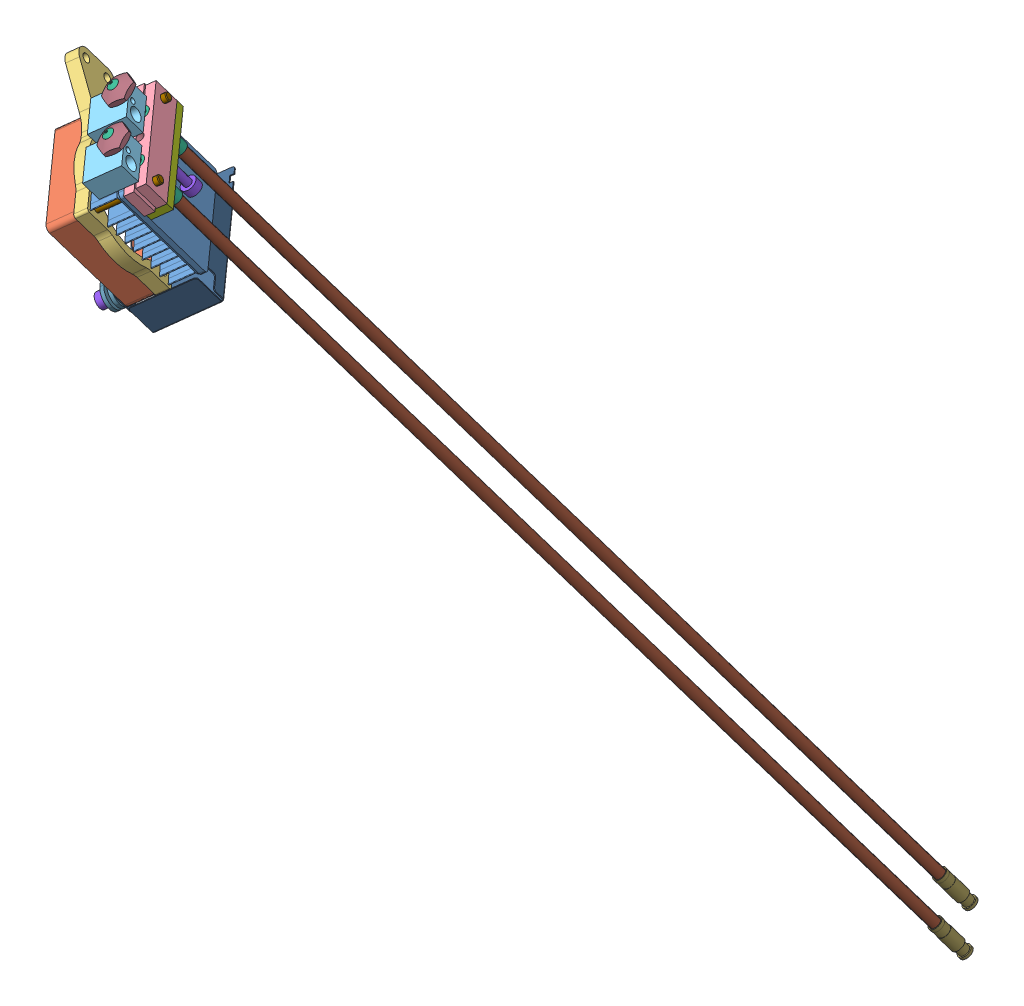
SolidWorks assembly 838, configuration Default. Lengths in mm.
Overall size (182.74 333.87 245.17).
23 component instances, 15 part files, 53 mates.
Components (placement in the parent):
- 357-1: 357 [Default] at (71.5589 -24.0668 51.2021) x (-0.63863 0.214399 -0.739043) z (-0.330371 0.790997 0.514955) size (40 13 40)
- 846-1: 846 [Default] at (59.0492 -34.3813 59.0199) x (-0.63863 0.214399 -0.739043) z (-0.694987 -0.573024 0.434323) size (40 40 10)
- 741-1: 741 [Default] at (59.0492 -34.3813 59.0199) x (0.63863 -0.214399 0.739043) z (0.694987 0.573024 -0.434323) size (59.3 52.5 5)
- 736-1: 736 [Default] at (67.7315 -5.9548 59.7639) x (0.63863 -0.214399 0.739043) z (0.330371 -0.790997 -0.514955) size (42 8 10)
- 739-1: 739 [Default] at (72.4173 -14.8335 80.8745) x (0.694987 0.573024 -0.434323) z (-0.330371 0.790997 0.514955) size (14 14 8)
- 739-2: 739 [Default] at (60.2862 -10.7609 66.8361) x (0.694987 0.573024 -0.434323) z (-0.330371 0.790997 0.514955) size (14 14 8)
- 738-2: 738 [Default] at (79.9671 -22.764 57.1656) x (0.082226 -0.519395 0.850569) z (-0.330371 0.790997 0.514955) size (5 5 33.2)
- 738-3: 738 [Default] at (67.8361 -18.6914 43.1272) x (0.499266 -0.316556 0.806552) z (-0.330371 0.790997 0.514955) size (5 5 33.2)
- 743-1: 743 [Default] at (70.3402 -14.4378 55.0487) x (-0.63863 0.214399 -0.739043) z (0.330371 -0.790997 -0.514955) size (40 8 3)
- 242-1: 242 [Default] at (75.3286 -24.1473 47.9182) x (-0.941272 -0.316416 -0.117844) z (0.330371 -0.790997 -0.514955) size (5.7 5.7 19)
- 520-1: 520 [Default] at (59.1164 -29.1669 82.1241) x (-0.685251 0.344906 -0.64146) z (-0.694987 -0.573024 0.434323) size (5.7 5.7 38)
- 520-2: 520 [Default] at (38.6803 -22.3061 58.4748) x (0.397421 0.197255 0.896185) z (-0.694987 -0.573024 0.434323) size (5.7 5.7 38)
- 891-1: 891 [Default] at (34.0047 -22.8308 58.1292) x (0.330371 -0.790997 -0.514955) z (-0.694987 -0.573024 0.434323) size (19.51 52.71 25.91)
- 242-2: 242 [Default] at (64.3021 -58.9197 69.0116) x (0.494952 -0.819418 -0.289096) z (-0.694987 -0.573024 0.434323) size (5.7 5.7 19)
- 242-3: 242 [Default] at (46.8892 -49.5663 43.4729) x (0.494952 -0.819418 -0.289096) z (-0.694987 -0.573024 0.434323) size (5.7 5.7 19)
- 219-1: 219 [Default] at (190.6262 -312.6844 -148.2683) x (0.896188 0.091701 0.434094) z (-0.330371 0.790997 0.514955) size (4 4 380)
- 219-2: 219 [Default] at (202.7573 -316.757 -134.2298) x (0.896188 0.091701 0.434094) z (-0.330371 0.790997 0.514955) size (4 4 380)
- 106-1: 106 [Default] at (199.6549 -309.3291 -129.3941) x (0.541182 0.605747 -0.58326) z (0.330371 -0.790997 -0.514955) size (5 5 15)
- 106-2: 106 [Default] at (187.5238 -305.2565 -143.4325) x (0.541182 0.605747 -0.58326) z (0.330371 -0.790997 -0.514955) size (5 5 15)
- 794-1: 794 [Default] at (70.3942 0.1562 72.0872) x (0.896188 0.091701 0.434094) z (-0.330371 0.790997 0.514955) size (11.55 10 4.01)
- 794-2: 794 [Default] at (58.2631 4.2288 58.0487) x (0.896188 0.091701 0.434094) z (-0.330371 0.790997 0.514955) size (11.55 10 4.01)
- 841-1: 841 [Default] at (56.454 -52.6174 63.6171) x (0.63863 -0.214399 0.739043) z (0.330371 -0.790997 -0.514955) size (19 7.7 9.6)
- 212-1: 212 [Default] at (64.3021 -58.9197 69.0116) x (-0.547984 0.031038 -0.835912) z (0.694987 0.573024 -0.434323) size (7 7 0.5)
Mates (geometry in assembly coordinates):
- Coincident327: coincident anti-aligned: circle of 738-2; plane of 738-3 through (56.8348 7.8683 60.6713) normal (-0.330371 0.790997 0.514955)
- Concentric245: concentric anti-aligned: cylinder of 739-1 through (70.3942 0.1562 72.0872) axis (-0.330371 0.790997 0.514955) radius 1.65; cylinder of 738-2 through (79.9671 -22.764 57.1656) axis (0.330371 -0.790997 -0.514955) radius 2.5
- Concentric246: concentric anti-aligned: cylinder of 739-2 through (58.2631 4.2288 58.0487) axis (-0.330371 0.790997 0.514955) radius 1.65; cylinder of 738-3 through (67.8361 -18.6914 43.1272) axis (0.330371 -0.790997 -0.514955) radius 2
- Coincident331: coincident anti-aligned: plane of 739-1 through (63.4764 -11.8319 70.5279) normal (0.330371 -0.790997 -0.514955); plane of 738-2 through (73.2263 -7.3664 69.9238) normal (-0.330371 0.790997 0.514955)
- Coincident333: coincident anti-aligned: plane of 846-1 through (59.0492 -34.3813 59.0199) normal (0.694987 0.573024 -0.434323); plane of 741-1 through (59.0492 -34.3813 59.0199) normal (-0.694987 -0.573024 0.434323)
- Coincident335: coincident aligned: plane of 739-1 through (63.4764 -11.8319 70.5279) normal (0.330371 -0.790997 -0.514955); plane of 739-2 through (51.3453 -7.7593 56.4895) normal (0.330371 -0.790997 -0.514955)
- Concentric259: concentric anti-aligned: cylinder of 743-1 through (72.0249 -16.2373 53.0678) axis (-0.330371 0.790997 0.514955) radius 2.2; cylinder of 242-1 through (70.0426 -11.4913 56.1575) axis (0.330371 -0.790997 -0.514955) radius 1.5
- Distance2: distance = 10 mm anti-aligned: plane of 242-1 through (75.3286 -24.1473 47.9182) normal (-0.330371 0.790997 0.514955); plane of 743-1 through (71.3313 -16.8108 53.5038) normal (0.330371 -0.790997 -0.514955)
- Coincident345: coincident anti-aligned: plane of 846-1 through (59.0492 -34.3813 59.0199) normal (0.694987 0.573024 -0.434323); plane of 741-1 through (59.0492 -34.3813 59.0199) normal (-0.694987 -0.573024 0.434323)
- Concentric263: concentric aligned: cylinder of 846-1 through (38.6803 -22.3061 58.4748) axis (-0.694987 -0.573024 0.434323) radius 3.1; cylinder of 741-1 through (47.0201 -15.4298 53.2629) axis (-0.694987 -0.573024 0.434323) radius 1.6
- Concentric264: concentric aligned: cylinder of 846-1 through (59.1164 -29.1669 82.1241) axis (-0.694987 -0.573024 0.434323) radius 3.1; cylinder of 741-1 through (67.4563 -22.2906 76.9122) axis (-0.694987 -0.573024 0.434323) radius 1.6
- Concentric265: concentric anti-aligned: cylinder of 357-1 through (69.5412 -20.5715 75.6093) axis (0.694987 0.573024 -0.434323) radius 1.6; cylinder of 846-1 through (59.1164 -29.1669 82.1241) axis (-0.694987 -0.573024 0.434323) radius 3.1
- Coincident355: coincident anti-aligned: plane of 357-1 through (62.5241 -31.5162 56.8483) normal (-0.694987 -0.573024 0.434323); plane of 741-1 through (62.5241 -31.5162 56.8483) normal (0.694987 0.573024 -0.434323)
- Concentric273: concentric anti-aligned: cylinder of 357-1 through (49.1051 -13.7107 51.9599) axis (0.694987 0.573024 -0.434323) radius 1.6; cylinder of 846-1 through (38.6803 -22.3061 58.4748) axis (-0.694987 -0.573024 0.434323) radius 3.1
- Concentric276: concentric aligned: cylinder of 846-1 through (63.9813 -25.1557 79.0839) axis (-0.694987 -0.573024 0.434323) radius 1.6; cylinder of 520-1 through (83.441 -9.111 66.9228) axis (-0.694987 -0.573024 0.434323) radius 1.5
- Coincident357: coincident anti-aligned: circle of 846-1; plane of 520-1 through (59.1164 -29.1669 82.1241) normal (0.694987 0.573024 -0.434323)
- Concentric277: concentric aligned: cylinder of 846-1 through (38.6803 -22.3061 58.4748) axis (-0.694987 -0.573024 0.434323) radius 3.1; cylinder of 520-2 through (63.0048 -2.2503 43.2734) axis (-0.694987 -0.573024 0.434323) radius 1.5
- Coincident358: coincident anti-aligned: circle of 846-1; plane of 520-2 through (38.6803 -22.3061 58.4748) normal (0.694987 0.573024 -0.434323)
- Concentric280: concentric aligned: cylinder of 846-1 through (69.6883 -54.4788 65.6456) axis (-0.694987 -0.573024 0.434323) radius 3.1; circle of 891-1
- Coincident360: coincident anti-aligned: plane of 846-1 through (52.0993 -40.1115 63.3631) normal (-0.694987 -0.573024 0.434323); plane of 891-1 through (34.2827 -22.6016 57.9555) normal (0.694987 0.573024 -0.434323)
- Concentric284: concentric aligned: cylinder of 738-3 through (67.8361 -18.6914 43.1272) axis (0.330371 -0.790997 -0.514955) radius 2.5; circle of 743-1
- Coincident361: coincident anti-aligned: plane of 357-1 through (89.4855 -42.6667 55.3477) normal (0.694987 0.573024 -0.434323); plane of 736-1 through (55.4841 -11.8694 41.5724) normal (-0.694987 -0.573024 0.434323)
- Concentric285: concentric anti-aligned: cylinder of 736-1 through (77.1007 -15.9011 61.6336) axis (-0.330371 0.790997 0.514955) radius 2.5; cylinder of 738-2 through (79.9671 -22.764 57.1656) axis (0.330371 -0.790997 -0.514955) radius 2.5
- Concentric286: concentric anti-aligned: circle of 736-1; cylinder of 738-3 through (67.8361 -18.6914 43.1272) axis (0.330371 -0.790997 -0.514955) radius 2.5
- Concentric287: concentric aligned: circle of 736-1; circle of 520-1
- Concentric288: concentric aligned: circle of 736-1; circle of 520-2
- Concentric289: concentric aligned: circle of 846-1; circle of 891-1
- Coincident362: coincident aligned: plane of 736-1 through (61.6659 -3.9185 52.7446) normal (-0.330371 0.790997 0.514955); plane of 738-3 through (62.34 -4.3458 53.8335) normal (-0.330371 0.790997 0.514955)
- Parallel3: parallel aligned: plane of 736-1 through (81.665 -20.6588 71.8698) normal (0.63863 -0.214399 0.739043); plane of 739-1 through (69.7743 -8.5055 84.9942) normal (0.63863 -0.214399 0.739043)
- Coincident363: coincident anti-aligned: plane of 736-1 through (64.9696 -11.8285 47.5951) normal (0.330371 -0.790997 -0.514955); plane of 743-1 through (70.3402 -14.4378 55.0487) normal (-0.330371 0.790997 0.514955)
- Concentric290: concentric aligned: circle of 891-1; cylinder of 242-2 through (75.4219 -49.7513 62.0624) axis (-0.694987 -0.573024 0.434323) radius 1.5
- Concentric291: concentric aligned: circle of 891-1; cylinder of 242-3 through (58.009 -40.3979 36.5237) axis (-0.694987 -0.573024 0.434323) radius 1.5
- Coincident365: coincident aligned: plane of 891-1 through (34.0047 -22.8308 58.1292) normal (-0.694987 -0.573024 0.434323); circle of 242-3
- Coincident366: coincident: cone of 738-3 through (65.0357 -11.9867 47.4921) axis (-0.330371 0.790997 0.514955); circle of 219-1
- Concentric292: concentric aligned: cylinder of 738-3 through (67.8361 -18.6914 43.1272) axis (0.330371 -0.790997 -0.514955) radius 2.5; cylinder of 219-1 through (65.0853 -12.1055 47.4147) axis (0.330371 -0.790997 -0.514955) radius 2
- Concentric293: concentric aligned: cylinder of 738-2 through (79.9671 -22.764 57.1656) axis (0.330371 -0.790997 -0.514955) radius 1.75; cylinder of 219-2 through (77.2164 -16.1781 61.4532) axis (0.330371 -0.790997 -0.514955) radius 2
- Parallel4: parallel aligned: plane of 736-1 through (86.5863 -15.8602 67.6562) normal (0.694987 0.573024 -0.434323); plane of 743-1 through (74.8062 -13.9457 51.3322) normal (0.694987 0.573024 -0.434323)
- Coincident367: coincident aligned: plane of 219-1 through (190.6262 -312.6844 -148.2683) normal (0.330371 -0.790997 -0.514955); plane of 219-2 through (202.7573 -316.757 -134.2298) normal (0.330371 -0.790997 -0.514955)
- Concentric294: concentric anti-aligned: cylinder of 219-2 through (77.2164 -16.1781 61.4532) axis (0.330371 -0.790997 -0.514955) radius 2; cylinder of 106-1 through (204.6104 -321.194 -137.1184) axis (-0.330371 0.790997 0.514955) radius 2.5
- Coincident368: coincident: circle of 219-2; cone of 106-1 through (202.6282 -316.4481 -134.0287) axis (0.330371 -0.790997 -0.514955)
- Concentric295: concentric anti-aligned: cylinder of 219-1 through (65.0853 -12.1055 47.4147) axis (0.330371 -0.790997 -0.514955) radius 2; cylinder of 106-2 through (192.4794 -317.1214 -151.1569) axis (-0.330371 0.790997 0.514955) radius 2.5
- Coincident369: coincident aligned: plane of 106-1 through (204.6104 -321.194 -137.1184) normal (0.330371 -0.790997 -0.514955); plane of 106-2 through (192.4794 -317.1214 -151.1569) normal (0.330371 -0.790997 -0.514955)
- Parallel7: parallel aligned: plane of 739-1 through (69.7743 -8.5055 84.9942) normal (-0.694987 -0.573024 0.434323); plane of 739-2 through (57.6432 -4.4329 70.9557) normal (-0.694987 -0.573024 0.434323)
- Coincident370: coincident anti-aligned: plane of 739-1 through (60.8335 -5.5039 74.6476) normal (-0.330371 0.790997 0.514955); plane of 794-1 through (70.3942 0.1562 72.0872) normal (0.330371 -0.790997 -0.514955)
- Concentric296: concentric aligned: cylinder of 738-2 through (79.9671 -22.764 57.1656) axis (0.330371 -0.790997 -0.514955) radius 2; circle of 794-1
- Concentric297: concentric aligned: circle of 738-3; cylinder of 794-2 through (58.2631 4.2288 58.0487) axis (0.330371 -0.790997 -0.514955) radius 1.65
- Coincident371: coincident anti-aligned: plane of 739-2 through (48.7024 -1.4313 60.6091) normal (-0.330371 0.790997 0.514955); plane of 794-2 through (58.2631 4.2288 58.0487) normal (0.330371 -0.790997 -0.514955)
- Concentric298: concentric aligned: cylinder of 891-1 through (67.6033 -56.1979 66.9485) axis (-0.694987 -0.573024 0.434323) radius 1.7; circle of 841-1
- Parallel10: parallel anti-aligned: plane of 891-1 through (16.763 -88.5777 53.9549) normal (0.330371 -0.790997 -0.514955); plane of 841-1 through (56.454 -52.6174 63.6171) normal (-0.330371 0.790997 0.514955)
- Coincident372: coincident anti-aligned: plane of 891-1 through (34.0047 -22.8308 58.1292) normal (-0.694987 -0.573024 0.434323); plane of 841-1 through (62.3013 -58.0048 57.0014) normal (0.694987 0.573024 -0.434323)
- Coincident373: coincident anti-aligned: plane of 841-1 through (59.6256 -60.211 58.6735) normal (-0.694987 -0.573024 0.434323); circle of 212-1
- Concentric299: concentric anti-aligned: cylinder of 242-2 through (75.4219 -49.7513 62.0624) axis (-0.694987 -0.573024 0.434323) radius 1.5; circle of 212-1
- Coincident374: coincident anti-aligned: plane of 242-2 through (64.3021 -58.9197 69.0116) normal (0.694987 0.573024 -0.434323); plane of 212-1 through (64.3021 -58.9197 69.0116) normal (-0.694987 -0.573024 0.434323)
